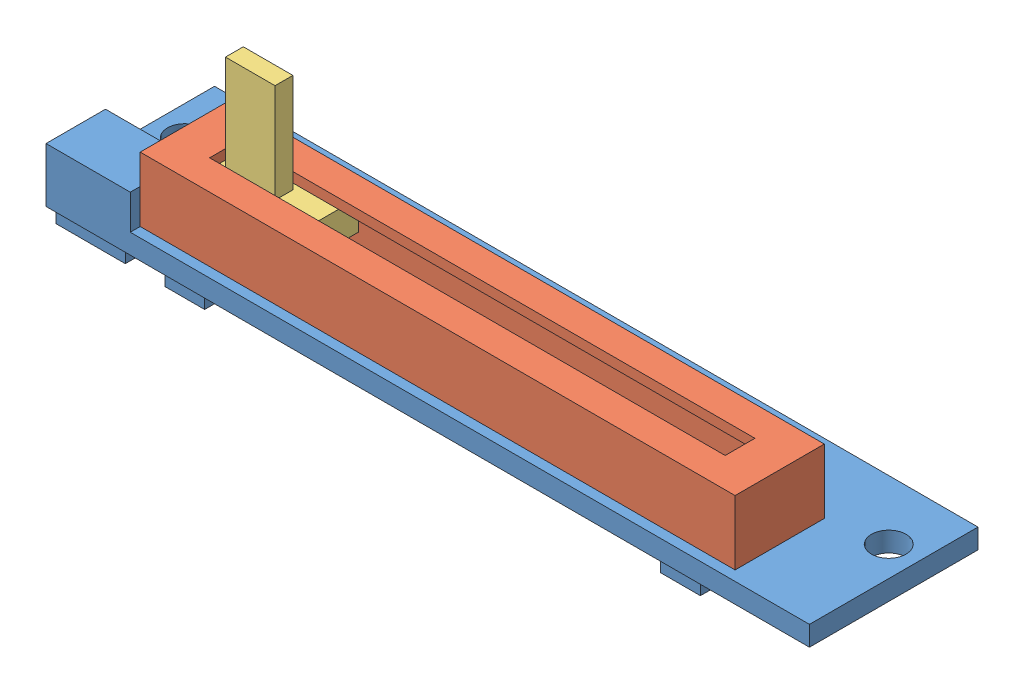
SolidWorks assembly Assemblage_Glissiere, configuration Défaut. Lengths in mm.
Overall size (77 19 17).
3 component instances, 3 part files, 6 mates.
Components (placement in the parent):
- Glissiere_pc1-1: Glissiere_pc1 [Défaut] at origin size (77 7 17)
- Glissiere_pc2-1: Glissiere_pc2 [Défaut] at (68.5 8.5 -1) x (-1 0 0) z (0 0 1) size (60 7.5 9)
- Glissiere_pc3-1: Glissiere_pc3 [Défaut] at (22.5 4.5 -9) x (-1 0 0) z (0 1 0) size (13 7 13)
Mates (geometry in assembly coordinates):
- DistanceLimite3: limit distance = 0 mm anti-aligned: plane of Glissiere_pc3-1 through (9.5 7.5 -9) normal (-1 0 0); plane of Glissiere_pc2-1 through (9.5 1 -9) normal (1 0 0)
- Coïncidente2: coincident anti-aligned: plane of Glissiere_pc2-1 through (67.5 1 -9) normal (0 0 1); plane of Glissiere_pc3-1 through (22.5 7.5 -9) normal (0 0 -1)
- Coïncidente3: coincident anti-aligned: plane of Glissiere_pc2-1 through (68.5 7.5 -1) normal (0 -1 0); plane of Glissiere_pc3-1 through (22.5 7.5 -9) normal (0 1 0)
- Coïncidente11: coincident anti-aligned: plane of Glissiere_pc1-1 through (0 1 0) normal (0 1 0); plane of Glissiere_pc2-1 through (68.5 1 -1) normal (0 -1 0)
- Coïncidente12: coincident anti-aligned: plane of Glissiere_pc1-1 through (8.5 1 -10) normal (0 0 1); plane of Glissiere_pc2-1 through (68.5 7.5 -10) normal (0 0 -1)
- Coïncidente13: coincident anti-aligned: plane of Glissiere_pc1-1 through (68.5 1 -10) normal (-1 0 0); plane of Glissiere_pc2-1 through (68.5 7.5 -1) normal (1 0 0)
